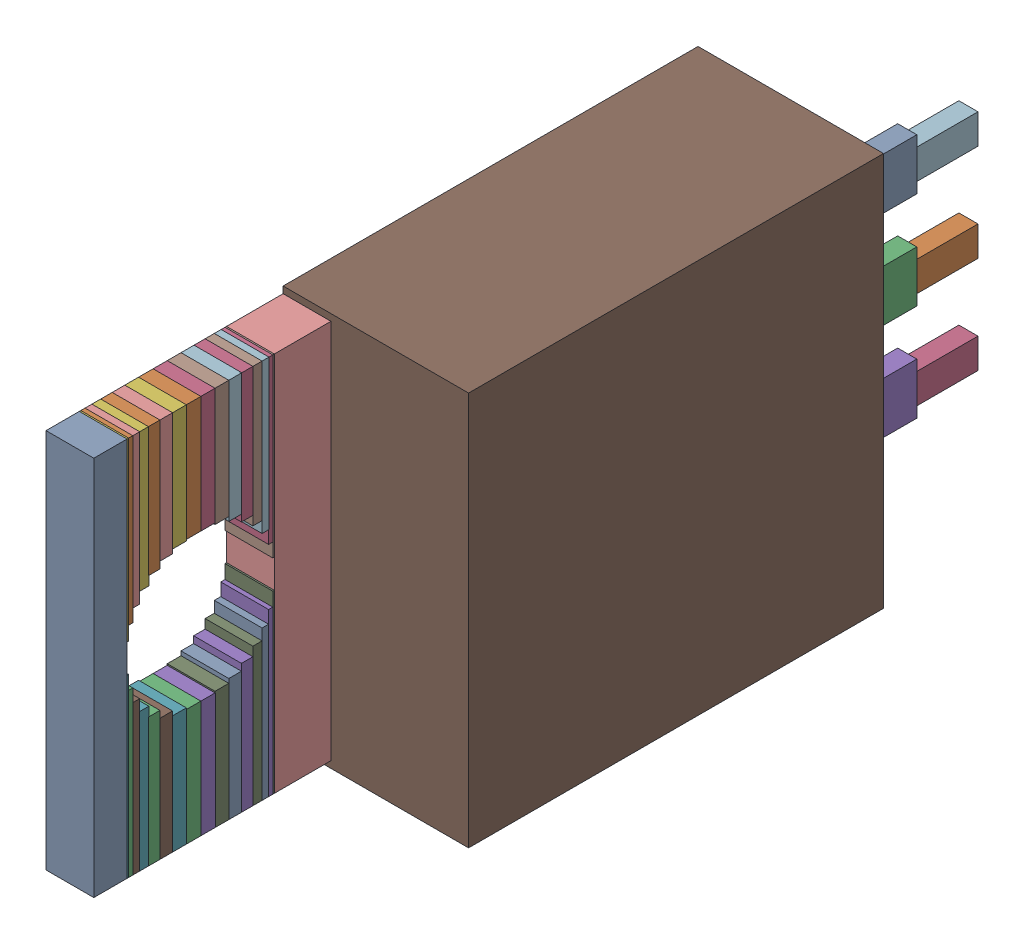
SolidWorks assembly Q1.step, configuration Default. Lengths in mm.
Overall size (4.85 10.3 21.45).
82 component instances, 18 part files, 0 mates.
Components (placement in the parent):
- 6100337184.step-1: 6100337184.step [Default] at (101.206 53.34 18.98) size (1.25 9.95 0.87)
  - Extruded.step-1: Extruded.step [Default] at origin size (1.25 9.95 0.87)
- 6100336784.step-1: 6100336784.step [Default] at (101.206 56.79 17.05) size (1.25 3.05 0.38)
  - Extruded-8.step-1: Extruded-8.step [Default] at origin size (1.25 3.05 0.38)
- 6100336784.step-2: 6100336784.step [Default] at (101.206 49.89 17.05) size (1.25 3.05 0.38)
  - Extruded-8.step-1: Extruded-8.step [Default] at origin size (1.25 3.05 0.38)
- 6100335504.step-1: 6100335504.step [Default] at (101.206 56.79 16.67) size (1.25 3.05 0.38)
  - Extruded-9.step-1: Extruded-9.step [Default] at origin size (1.25 3.05 0.38)
- 6100335504.step-2: 6100335504.step [Default] at (101.206 49.89 16.67) size (1.25 3.05 0.38)
  - Extruded-9.step-1: Extruded-9.step [Default] at origin size (1.25 3.05 0.38)
- 6100342224.step-1: 6100342224.step [Default] at (101.206 56.7715 17.43) size (1.25 3.09 0.36)
  - Extruded-10.step-1: Extruded-10.step [Default] at origin size (1.25 3.09 0.36)
- 6100342224.step-2: 6100342224.step [Default] at (101.206 49.9085 17.43) size (1.25 3.09 0.36)
  - Extruded-10.step-1: Extruded-10.step [Default] at origin size (1.25 3.09 0.36)
- 6100331024.step-1: 6100331024.step [Default] at (101.206 56.7715 16.31) size (1.25 3.09 0.37)
  - Extruded-11.step-1: Extruded-11.step [Default] at origin size (1.25 3.09 0.37)
- 6100331024.step-2: 6100331024.step [Default] at (101.206 49.9085 16.31) size (1.25 3.09 0.37)
  - Extruded-11.step-1: Extruded-11.step [Default] at origin size (1.25 3.09 0.37)
- 6100330544.step-1: 6100330544.step [Default] at (101.206 56.7167 17.79) size (1.25 3.2 0.33)
  - Extruded-12.step-1: Extruded-12.step [Default] at origin size (1.25 3.2 0.33)
- 6100330544.step-2: 6100330544.step [Default] at (101.206 49.9633 17.79) size (1.25 3.2 0.33)
  - Extruded-12.step-1: Extruded-12.step [Default] at origin size (1.25 3.2 0.33)
- 6100330224.step-1: 6100330224.step [Default] at (101.206 56.7167 15.98) size (1.25 3.2 0.34)
  - Extruded-13.step-1: Extruded-13.step [Default] at origin size (1.25 3.2 0.34)
- 6100330224.step-2: 6100330224.step [Default] at (101.206 49.9633 15.98) size (1.25 3.2 0.34)
  - Extruded-13.step-1: Extruded-13.step [Default] at origin size (1.25 3.2 0.34)
- 6100325984.step-1: 6100325984.step [Default] at (101.206 56.6278 18.12) size (1.25 3.37 0.3)
  - Extruded-14.step-1: Extruded-14.step [Default] at origin size (1.25 3.37 0.3)
- 6100325984.step-2: 6100325984.step [Default] at (101.206 50.0522 18.12) size (1.25 3.37 0.3)
  - Extruded-14.step-1: Extruded-14.step [Default] at origin size (1.25 3.37 0.3)
- 6100325984.step-3: 6100325984.step [Default] at (101.206 56.6278 15.69) size (1.25 3.37 0.3)
  - Extruded-14.step-1: Extruded-14.step [Default] at origin size (1.25 3.37 0.3)
- 6100325984.step-4: 6100325984.step [Default] at (101.206 50.0522 15.69) size (1.25 3.37 0.3)
  - Extruded-14.step-1: Extruded-14.step [Default] at origin size (1.25 3.37 0.3)
- 6100325824.step-1: 6100325824.step [Default] at (101.206 56.5081 18.41) size (1.25 3.61 0.25)
  - Extruded-15.step-1: Extruded-15.step [Default] at origin size (1.25 3.61 0.25)
- 6100325824.step-2: 6100325824.step [Default] at (101.206 50.1719 18.41) size (1.25 3.61 0.25)
  - Extruded-15.step-1: Extruded-15.step [Default] at origin size (1.25 3.61 0.25)
- 6100326864.step-1: 6100326864.step [Default] at (101.206 56.5081 15.45) size (1.25 3.61 0.24)
  - Extruded-16.step-1: Extruded-16.step [Default] at origin size (1.25 3.61 0.24)
- 6100326864.step-2: 6100326864.step [Default] at (101.206 50.1719 15.45) size (1.25 3.61 0.24)
  - Extruded-16.step-1: Extruded-16.step [Default] at origin size (1.25 3.61 0.24)
- 6100326304.step-1: 6100326304.step [Default] at (101.206 56.3622 18.65) size (1.25 3.91 0.18)
  - Extruded-17.step-1: Extruded-17.step [Default] at origin size (1.25 3.91 0.18)
- 6100326304.step-2: 6100326304.step [Default] at (101.206 50.3178 18.65) size (1.25 3.91 0.18)
  - Extruded-17.step-1: Extruded-17.step [Default] at origin size (1.25 3.91 0.18)
- 6100326304.step-3: 6100326304.step [Default] at (101.206 56.3622 15.27) size (1.25 3.91 0.18)
  - Extruded-17.step-1: Extruded-17.step [Default] at origin size (1.25 3.91 0.18)
- 6100326304.step-4: 6100326304.step [Default] at (101.206 50.3178 15.27) size (1.25 3.91 0.18)
  - Extruded-17.step-1: Extruded-17.step [Default] at origin size (1.25 3.91 0.18)
- 6100326704.step-1: 6100326704.step [Default] at (101.206 56.1958 18.83) size (1.25 4.24 0.11)
  - Extruded-18.step-1: Extruded-18.step [Default] at origin size (1.25 4.24 0.11)
- 6100326704.step-2: 6100326704.step [Default] at (101.206 50.4842 18.83) size (1.25 4.24 0.11)
  - Extruded-18.step-1: Extruded-18.step [Default] at origin size (1.25 4.24 0.11)
- 6100327504.step-1: 6100327504.step [Default] at (101.206 56.1958 15.16) size (1.25 4.24 0.12)
  - Extruded-19.step-1: Extruded-19.step [Default] at origin size (1.25 4.24 0.12)
- 6100327504.step-2: 6100327504.step [Default] at (101.206 50.4842 15.16) size (1.25 4.24 0.12)
  - Extruded-19.step-1: Extruded-19.step [Default] at origin size (1.25 4.24 0.12)
- 6100327344.step-1: 6100327344.step [Default] at (101.206 56.0153 18.94) size (1.25 4.6 0.04)
  - Extruded-20.step-1: Extruded-20.step [Default] at origin size (1.25 4.6 0.04)
- 6100327344.step-2: 6100327344.step [Default] at (101.206 50.6647 18.94) size (1.25 4.6 0.04)
  - Extruded-20.step-1: Extruded-20.step [Default] at origin size (1.25 4.6 0.04)
- 6100327344.step-3: 6100327344.step [Default] at (101.206 56.0153 15.13) size (1.25 4.6 0.04)
  - Extruded-20.step-1: Extruded-20.step [Default] at origin size (1.25 4.6 0.04)
- 6100327344.step-4: 6100327344.step [Default] at (101.206 50.6647 15.13) size (1.25 4.6 0.04)
  - Extruded-20.step-1: Extruded-20.step [Default] at origin size (1.25 4.6 0.04)
- 6100330864.step-1: 6100330864.step [Default] at (101.206 53.34 13.65) size (1.25 9.95 1.48)
  - Extruded-21.step-1: Extruded-21.step [Default] at origin size (1.25 9.95 1.48)
- 6100331424.step-1: 6100331424.step [Default] at (103.006 53.34 2.8) size (4.85 10.3 10.85)
  - Extruded-22.step-1: Extruded-22.step [Default] at origin size (4.85 10.3 10.85)
- 6100325584.step-1: 6100325584.step [Default] at (103.251 55.88 -1.6) size (0.5 0.78 1.6)
  - Extruded-23.step-1: Extruded-23.step [Default] at origin size (0.5 0.78 1.6)
- 6138241984.step-1: 6138241984.step [Default] at (103.251 55.88 0) size (0.5 1.34 2.8)
  - Extruded-24.step-1: Extruded-24.step [Default] at origin size (0.5 1.34 2.8)
- 6100325584.step-2: 6100325584.step [Default] at (103.251 53.34 -1.6) size (0.5 0.78 1.6)
  - Extruded-23.step-1: Extruded-23.step [Default] at origin size (0.5 0.78 1.6)
- 6138241984.step-2: 6138241984.step [Default] at (103.251 53.34 0) size (0.5 1.34 2.8)
  - Extruded-24.step-1: Extruded-24.step [Default] at origin size (0.5 1.34 2.8)
- 6100325584.step-3: 6100325584.step [Default] at (103.251 50.8 -1.6) size (0.5 0.78 1.6)
  - Extruded-23.step-1: Extruded-23.step [Default] at origin size (0.5 0.78 1.6)
- 6138241984.step-3: 6138241984.step [Default] at (103.251 50.8 0) size (0.5 1.34 2.8)
  - Extruded-24.step-1: Extruded-24.step [Default] at origin size (0.5 1.34 2.8)
